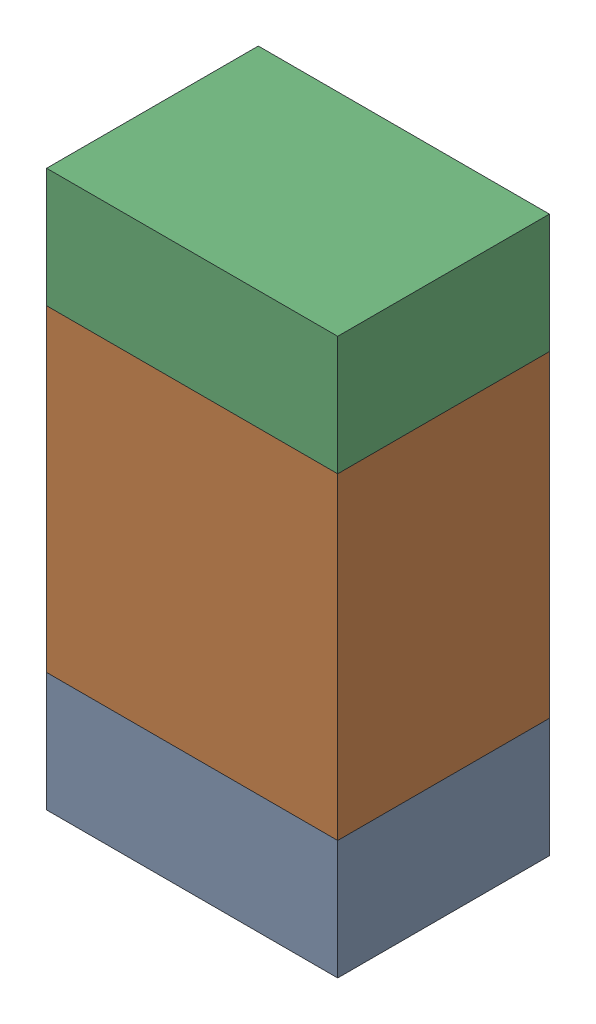
SolidWorks assembly R106_2PCB, configuration Default. Lengths in mm.
Overall size (0.55 1.05 0.4).
6 component instances, 2 part files, 0 mates.
Components (placement in the parent):
- 846483288-1: 846483288 [Default] at (117.6999 87.5876 0) size (0.55 0.22 0.4)
  - Extruded_12-1: Extruded_12 [Default] at origin size (0.55 0.22 0.4)
- 846483424-1: 846483424 [Default] at (117.6999 88.0001 0) size (0.55 0.6 0.4)
  - Extruded_13-1: Extruded_13 [Default] at origin size (0.55 0.6 0.4)
- 846483288-2: 846483288 [Default] at (117.6999 88.4126 0) size (0.55 0.22 0.4)
  - Extruded_12-1: Extruded_12 [Default] at origin size (0.55 0.22 0.4)
